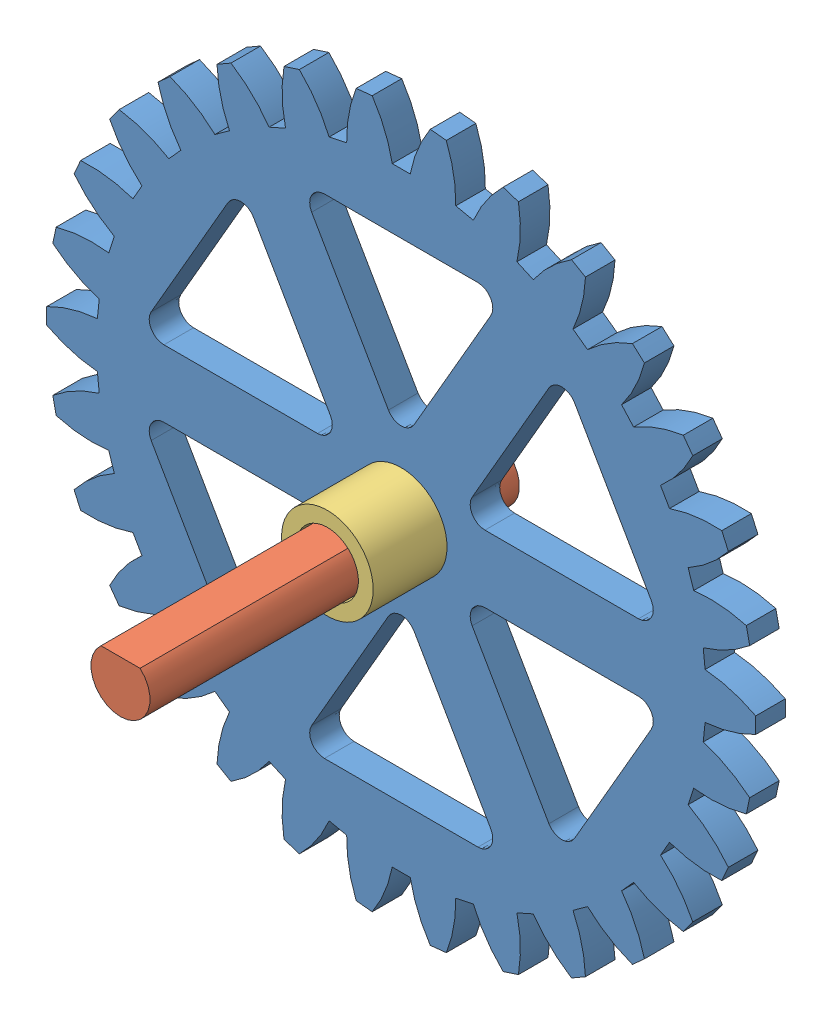
SolidWorks assembly Assem1, configuration Default. Lengths in mm.
Overall size (48 47.84 25).
4 component instances, 3 part files, 6 mates.
Components (placement in the parent):
- root_gear.-1: root_gear. [30T 1.5Mod] at (12.351 34.2341 32.5411) size (48 47.84 2)
- axle-1: axle [axle25] at (12.351 34.2341 28.5411) size (4 3.5 25)
- spacer-1: spacer [4.2] at (12.351 34.2341 34.5411) size (6.2 6.2 5)
- spacer-2: spacer [4.2 1mm] at (12.351 34.2341 31.5411) size (6.2 6.2 1)
Mates (geometry in assembly coordinates):
- Concentric1: concentric aligned: cylinder of root_gear.-1 through (12.351 34.2341 42.5411) axis (0 0 -1) radius 2; cylinder of axle-1 through (12.351 34.2341 53.5411) axis (0 0 -1) radius 2
- Concentric2: concentric aligned: cylinder of axle-1 through (12.351 34.2341 53.5411) axis (0 0 -1) radius 2; cylinder of spacer-2 through (12.351 34.2341 32.5411) axis (0 0 -1) radius 2.1
- Distance1: distance = 3 mm aligned: plane of axle-1 through (12.351 34.2341 28.5411) normal (0 0 -1); plane of spacer-2 through (12.351 34.2341 31.5411) normal (0 0 -1)
- Coincident2: coincident anti-aligned: plane of root_gear.-1 through (12.351 34.2341 32.5411) normal (0 0 -1); plane of spacer-2 through (12.351 34.2341 32.5411) normal (0 0 1)
- Concentric3: concentric aligned: cylinder of axle-1 through (12.351 34.2341 53.5411) axis (0 0 -1) radius 2; cylinder of spacer-1 through (12.351 34.2341 39.5411) axis (0 0 -1) radius 2.1
- Coincident3: coincident anti-aligned: plane of root_gear.-1 through (12.351 34.2341 34.5411) normal (0 0 1); plane of spacer-1 through (12.351 34.2341 34.5411) normal (0 0 -1)
